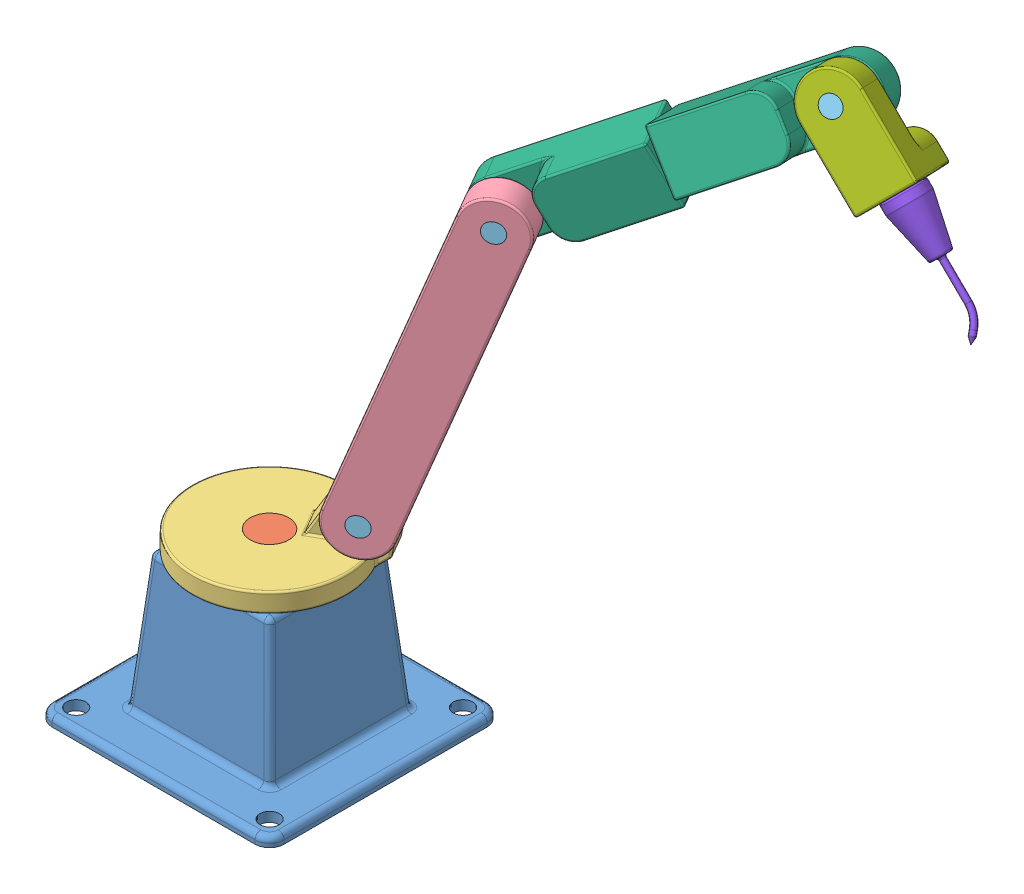
SolidWorks assembly Robot Arm Assembly_Distance, configuration Default. Lengths in mm.
Overall size (660.47 687.73 380.56).
13 component instances, 8 part files, 31 mates.
Components (placement in the parent):
- Base-1: Base [Default] at origin size (240 150 240)
- Pin_Long-1: Pin_Long [Default] x (0.735548 0 -0.677472) z (0.677472 0 0.735548) size (40 170 40)
- Link_T-1: Link_T [Default] at (0 150 0) x (0.866025 0 -0.5) z (0.5 0 0.866025) size (179.64 80.62 160)
- Link_Long-1: Link_Long [Default] at (94.3816 346.9287 -89.1323) x (0.296198 0.939693 -0.17101) z (0.5 0 0.866025) size (360 61.62 60)
- Pin_Short-1: Pin_Short [Default] at (79.9519 205.9749 -11.5192) x (0.75 0.5 -0.433013) z (-0.433013 0.866025 0.25) size (20 60 20)
- Link_Half-1: Link_Half [Default] at (281.3113 562.8826 -127.7742) x (0.75 0.5 -0.433013) z (-0.5 0 -0.866025) size (180 61.62 60)
- Pin_Short-2: Pin_Short [Default] at (168.8113 487.8826 -62.8223) x (0.75 0.5 -0.433013) z (-0.433013 0.866025 0.25) size (20 60 20)
- Pin_Short-3: Pin_Short [Default] at (243.8113 547.8826 -140.7645) x (0.164926 -0.775342 -0.609627) z (0.640546 -0.385805 0.663969) size (20 60 20)
- Link_Half-2: Link_Half [Default] at (275.9638 571.7686 -126.7758) x (-0.75 -0.5 0.433013) z (-0.321747 -0.296198 -0.899303) size (180 61.62 60)
- Link_End-1: Link_End [Default] at (425.1082 571.8279 -246.8737) x (0.699365 -0.71461 -0.014848) z (0.321747 0.296198 0.899303) size (110 61.62 60)
- Pin_Short-4: Pin_Short [Default] at (369.1589 628.9967 -245.6859) x (0.920135 -0.321747 -0.223228) z (-0.223228 -0.899303 0.376063) size (20 60 20)
- Pin_Short-5: Pin_Short [Default] at (455.7415 559.2755 -220.3401) x (0.705385 0.686685 0.175769) z (-0.115411 -0.1334 0.984319) size (20 60 20)
- Tool-1: Tool [Default] at (434.7606 580.7138 -219.8947) x (0.39187 0.400717 -0.828169) z (-0.597768 -0.573374 -0.560282) size (40 122.85 40)
Mates (geometry in assembly coordinates):
- Concentric1: concentric: cylinder of assembly; cylinder of assembly; cylinder of Base-1 through (0 150 0) axis (0 -1 0) radius 20; cylinder of Pin_Long-1 through (0 170 0) axis (0 -1 0) radius 20
- Concentric2: concentric: cylinder of assembly; cylinder of assembly; cylinder of Base-1 through (0 150 0) axis (0 -1 0) radius 20; cylinder of Link_T-1 through (0 170 0) axis (0 -1 0) radius 20
- Coincident1: coincident: plane of assembly; plane of assembly; plane of Base-1 through (0 150 0) normal (0 1 0); plane of Link_T-1 through (0 150 0) normal (0 -1 0)
- Coincident2: coincident: plane of assembly; plane of assembly; plane of Pin_Long-1 through (0 170 0) normal (0 1 0); plane of Link_T-1 through (0 170 0) normal (0 1 0)
- Angle1: planar angle = 0.523599 rad: plane of assembly through (0 0 0) normal (0 0 1); plane of assembly; plane of Link_T-1 through (0 150 0) normal (0.5 0 0.866025)
- Concentric3: concentric: cylinder of assembly; cylinder of assembly; cylinder of Link_T-1 through (49.9519 205.9749 -63.4808) axis (0.5 0 0.866025) radius 10; cylinder of Link_Long-1 through (79.9519 205.9749 -11.5192) axis (-0.5 0 -0.866025) radius 10
- Coincident4: coincident: plane of Link_T-1 through (64.9519 205.9749 -37.5) normal (0.5 0 0.866025); plane of Link_Long-1 through (109.3816 346.9287 -63.1515) normal (-0.5 0 -0.866025)
- Angle2: planar angle = 1.22173 rad: plane of Link_T-1 through (0 150 0) normal (0 1 0); plane of Link_Long-1 through (94.3816 346.9287 -89.1323) normal (-0.813798 0.34202 0.469846)
- Concentric4: concentric: cylinder of Link_Long-1 through (79.9519 205.9749 -11.5192) axis (-0.5 0 -0.866025) radius 10; cylinder of Pin_Short-1 through (49.9519 205.9749 -63.4808) axis (0.5 0 0.866025) radius 10
- Coincident6: coincident: plane of Link_Long-1 through (168.8113 487.8826 -62.8223) normal (0.5 0 0.866025); plane of Pin_Short-1 through (79.9519 205.9749 -11.5192) normal (0.5 0 0.866025)
- Concentric5: concentric: cylinder of Link_Long-1 through (168.8113 487.8826 -62.8223) axis (-0.5 0 -0.866025) radius 10; cylinder of ? through (170.2127 487.8826 -60.3951) axis (-0.5 0 -0.866025) radius 10
- Concentric6: concentric: cylinder of Link_Long-1 through (168.8113 487.8826 -62.8223) axis (-0.5 0 -0.866025) radius 10; cylinder of Link_Half-1 through (138.8113 487.8826 -114.7838) axis (0.5 0 0.866025) radius 10
- Coincident7: coincident: plane of Link_Long-1 through (109.3816 346.9287 -63.1515) normal (-0.5 0 -0.866025); plane of Link_Half-1 through (266.3113 562.8826 -153.7549) normal (0.5 0 0.866025)
- Concentric7: concentric: cylinder of Link_Long-1 through (168.8113 487.8826 -62.8223) axis (-0.5 0 -0.866025) radius 10; cylinder of Pin_Short-2 through (138.8113 487.8826 -114.7838) axis (0.5 0 0.866025) radius 10
- Coincident8: coincident: plane of Link_Long-1 through (168.8113 487.8826 -62.8223) normal (0.5 0 0.866025); plane of Pin_Short-2 through (168.8113 487.8826 -62.8223) normal (0.5 0 0.866025)
- Concentric8: concentric: cylinder of Link_Half-1 through (243.8113 547.8826 -140.7645) axis (0.75 0.5 -0.433013) radius 10; cylinder of Pin_Short-3 through (288.8113 577.8826 -166.7453) axis (-0.75 -0.5 0.433013) radius 10
- Coincident9: coincident: plane of Link_Half-1 through (243.8113 547.8826 -140.7645) normal (0.75 0.5 -0.433013); plane of Pin_Short-3 through (243.8113 547.8826 -140.7645) normal (-0.75 -0.5 0.433013)
- Angle3: planar angle = 0.698132 rad: plane of Link_Half-1 through (281.3113 562.8826 -127.7742) normal (0.433013 -0.866025 -0.25); plane of Link_Long-1 through (94.3816 346.9287 -89.1323) normal (-0.813798 0.34202 0.469846)
- Concentric9: concentric: cylinder of Pin_Short-3 through (288.8113 577.8826 -166.7453) axis (-0.75 -0.5 0.433013) radius 10; cylinder of Link_Half-2 through (288.8113 577.8826 -166.7453) axis (-0.75 -0.5 0.433013) radius 10
- Coincident11: coincident: plane of Pin_Short-3 through (288.8113 577.8826 -166.7453) normal (0.75 0.5 -0.433013); plane of Link_Half-2 through (288.8113 577.8826 -166.7453) normal (-0.75 -0.5 0.433013)
- Angle4: planar angle = 0.349066 rad: plane of Link_Half-1 through (281.3113 562.8826 -127.7742) normal (0.433013 -0.866025 -0.25); plane of Link_Half-2 through (275.9638 571.7686 -126.7758) normal (-0.577909 0.813798 -0.061275)
- Concentric10: concentric: cylinder of Link_Half-2 through (369.1589 628.9967 -245.6859) axis (0.321747 0.296198 0.899303) radius 10; cylinder of Link_End-1 through (388.4638 646.7686 -191.7278) axis (-0.321747 -0.296198 -0.899303) radius 10
- Coincident13: coincident: plane of Link_Half-2 through (266.3113 562.8826 -153.7549) normal (0.321747 0.296198 0.899303); plane of Link_End-1 through (434.7606 580.7138 -219.8947) normal (-0.321747 -0.296198 -0.899303)
- Concentric11: concentric: cylinder of Link_End-1 through (388.4638 646.7686 -191.7278) axis (-0.321747 -0.296198 -0.899303) radius 10; cylinder of Pin_Short-4 through (388.4638 646.7686 -191.7278) axis (-0.321747 -0.296198 -0.899303) radius 10
- Coincident14: coincident: plane of Link_End-1 through (388.4638 646.7686 -191.7278) normal (0.321747 0.296198 0.899303); plane of Pin_Short-4 through (388.4638 646.7686 -191.7278) normal (0.321747 0.296198 0.899303)
- Concentric12: concentric: cylinder of Link_End-1 through (413.7796 602.1521 -219.4492) axis (0.699365 -0.71461 -0.014848) radius 10; cylinder of Pin_Short-5 through (413.7796 602.1521 -219.4492) axis (0.699365 -0.71461 -0.014848) radius 10
- Coincident15: coincident: plane of Link_End-1 through (413.7796 602.1521 -219.4492) normal (0.699365 -0.71461 -0.014848); plane of Pin_Short-5 through (413.7796 602.1521 -219.4492) normal (-0.699365 0.71461 0.014848)
- Angle5: planar angle = 1.396263 rad: plane of Link_Half-2 through (275.9638 571.7686 -126.7758) normal (-0.577909 0.813798 -0.061275); plane of Link_End-1 through (425.1082 571.8279 -246.8737) normal (0.638253 0.633718 -0.437075)
- Concentric13: concentric: cylinder of Pin_Short-5 through (413.7796 602.1521 -219.4492) axis (0.699365 -0.71461 -0.014848) radius 10; cylinder of ? through (464.1339 550.7002 -220.5183) axis (0.699365 -0.71461 -0.014848) radius 10
- Coincident17: coincident: plane of Pin_Short-5 through (455.7415 559.2755 -220.3401) normal (0.699365 -0.71461 -0.014848); plane of ? through (455.7415 559.2755 -220.3401) normal (-0.699365 0.71461 0.014848)
- Angle6: planar angle = 0.523599 rad: plane of Link_End-1 through (425.1082 571.8279 -246.8737) normal (0.638253 0.633718 -0.437075); plane of Tool-1 through (434.7606 580.7138 -219.8947) normal (0.39187 0.400717 -0.828169)
